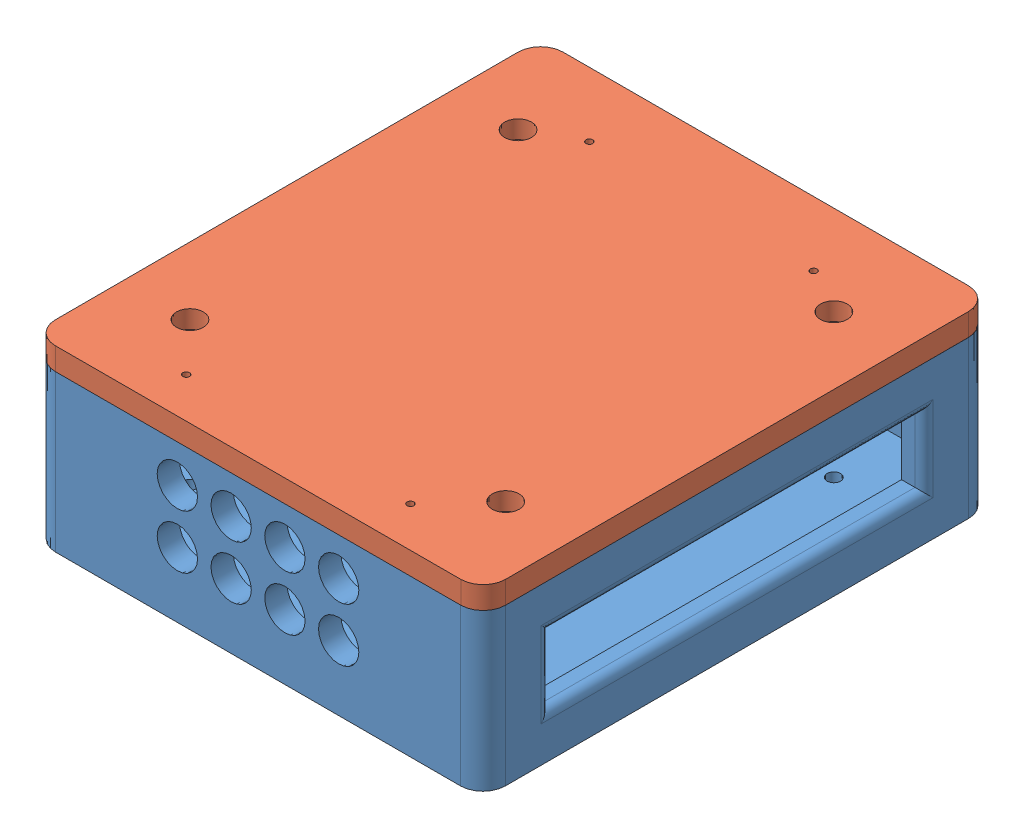
SolidWorks assembly POWERBOX_ASSEMBLED, configuration Default. Lengths in mm.
Overall size (100.51 40 113.54).
2 component instances, 2 part files, 3 mates.
Components (placement in the parent):
- Power Box-1: Power Box [Default] at origin size (100.4 35 113.4)
- power box top-1: power box top [Default] at (0.0371 35 0.0856) x (0.999999 0 -0.001011) z (0.001011 0 0.999999) size (100.4 10 113.4)
Mates (geometry in assembly coordinates):
- Coincident1: coordinate: point of Power Box-1
- Concentric1: concentric aligned: cylinder of Power Box-1 through (35.2 -1 -36.6) axis (0 1 0) radius 1.5; cylinder of power box top-1 through (35.2 23 -36.6) axis (0 1 0) radius 1.5
- Coincident3: coincident anti-aligned: plane of Power Box-1 through (0 35 0) normal (0 1 0); plane of power box top-1 through (0.0371 35 0.0856) normal (0 -1 0)
